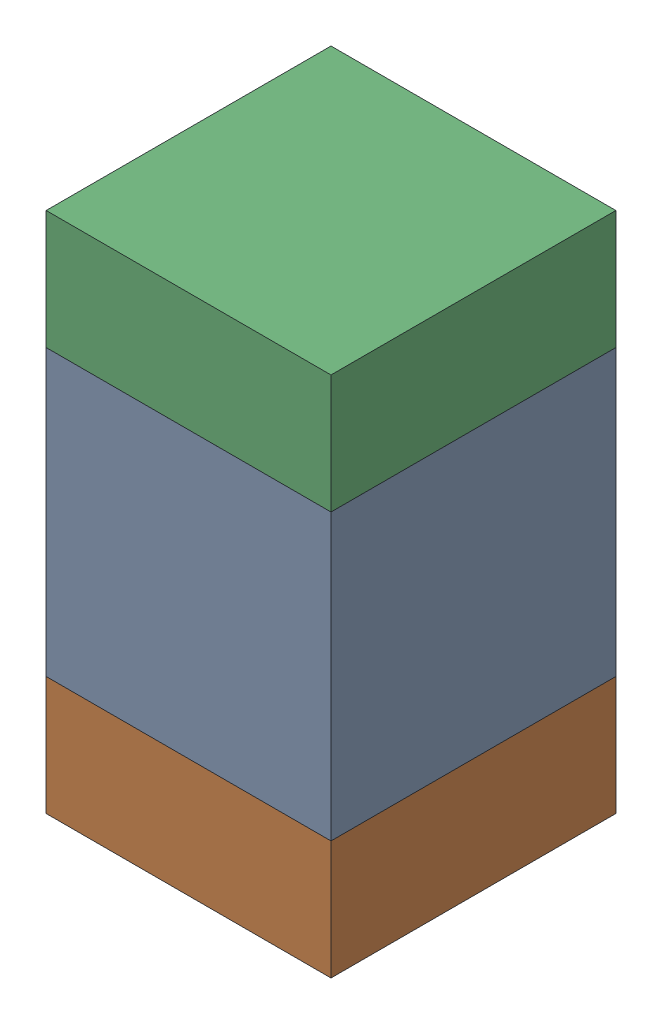
SolidWorks assembly C314_2PCB, configuration Default. Lengths in mm.
Overall size (0.6 1.1 0.6).
6 component instances, 2 part files, 0 mates.
Components (placement in the parent):
- 761606048-1: 761606048 [Default] at (126 93.3 -2.2638) size (0.6 0.6 0.6)
  - Extruded_9-1: Extruded_9 [Default] at origin size (0.6 0.6 0.6)
- 854785296-1: 854785296 [Default] at (126 92.875 -2.2638) size (0.6 0.25 0.6)
  - Extruded_10-1: Extruded_10 [Default] at origin size (0.6 0.25 0.6)
- 854785296-2: 854785296 [Default] at (126 93.725 -2.2638) size (0.6 0.25 0.6)
  - Extruded_10-1: Extruded_10 [Default] at origin size (0.6 0.25 0.6)
